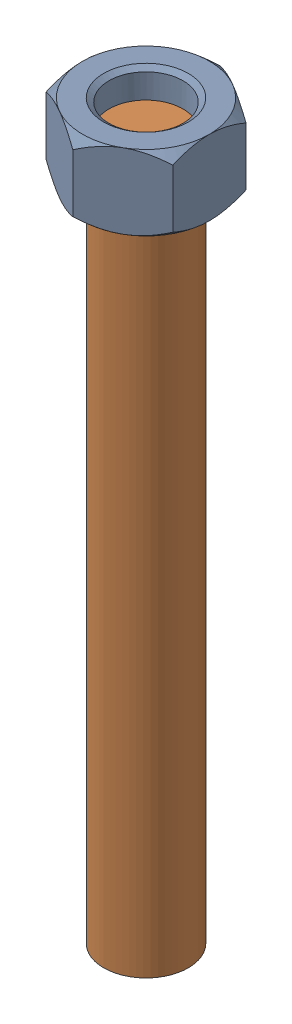
SolidWorks assembly 01-117-00-0-1, configuration Default. Lengths in mm.
Overall size (28.57 165.1 33).
2 component instances, 2 part files, 0 mates.
Components (placement in the parent):
- hex nut_ai(HNUT 0.7500-10-D-C)-1: hex nut_ai(HNUT 0.7500-10-D-C) [Default] at (0 165.1 0) x (1 0 0) z (0 1 0) size (28.57 33 16.89)
- TROD 0.7500-1x6.25-1: TROD 0.7500-1x6.25 [Default] at origin size (19.05 158.75 19.05)
